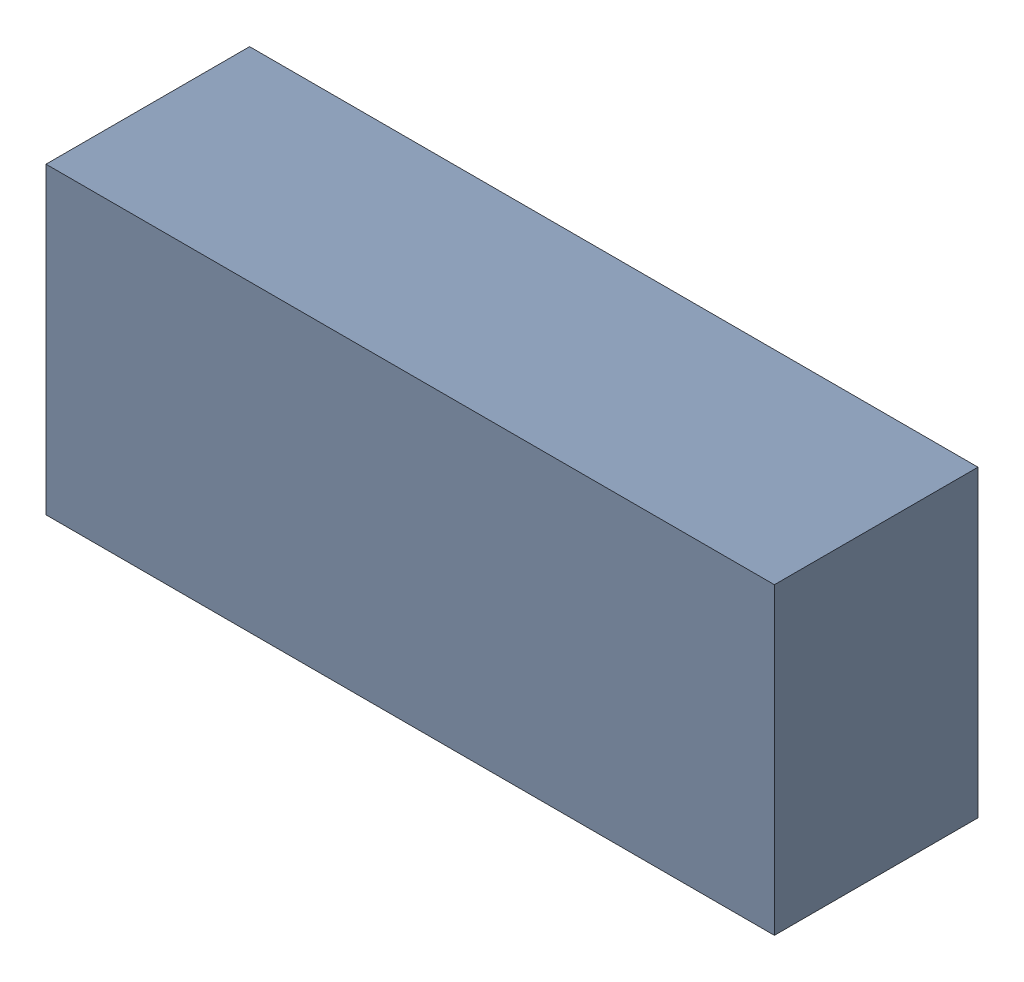
SolidWorks assembly P3, configuration Default. Lengths in mm.
Overall size (43.25 18.03 12.09).
2 component instances, 1 part files, 0 mates.
Components (placement in the parent):
- 975615248-1: 975615248 [Default] at (25.4 11.176 -12.5015) size (43.25 18.03 12.09)
  - Extruded_5-1: Extruded_5 [Default] at origin size (43.25 18.03 12.09)
